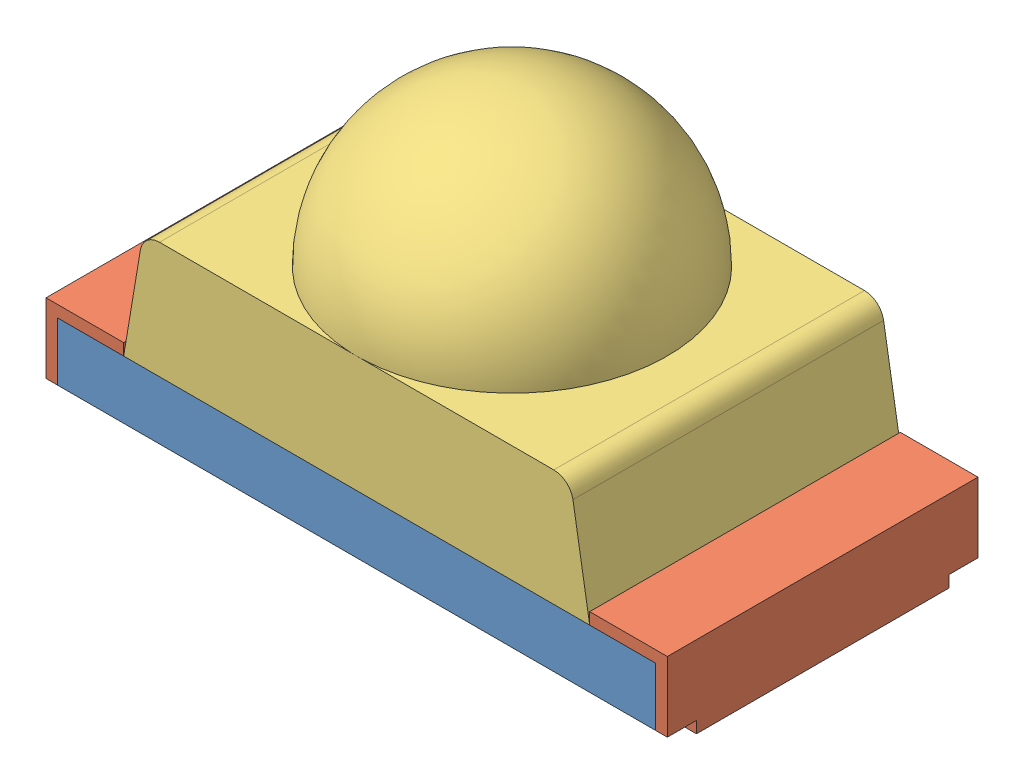
SolidWorks assembly LED0603G, configuration Default. Lengths in mm.
Overall size (1.6 0.88 0.8).
4 component instances, 3 part files, 9 mates.
Components (placement in the parent):
- LED0603-substrate-1: LED0603-substrate [Default] at (0 0.03 0) size (1.54 0.15 0.8)
- LED0603-clip-1: LED0603-clip [Default] at (-0.8 0.105 0) x (1 0 0) z (0 1 0) size (0.3 0.8 0.21)
- LED0603-clip-2: LED0603-clip [Default] at (0.8 0.105 0) x (-1 0 0) z (0 1 0) size (0.3 0.8 0.21)
- LED0603-lens-1: LED0603-lens [Default] at (0 0.18 0) size (1.2 0.7 0.8)
Mates (geometry in assembly coordinates):
- Coincident1: coincident aligned: plane of LED0603-substrate-1 through (0 0.03 0) normal (1 0 0)
- Coincident2: coincident aligned: plane of LED0603-substrate-1 through (0 0.03 0) normal (0 0 1)
- Distance1: distance = 0.03 mm aligned: plane of LED0603-substrate-1 through (0 0.03 0) normal (0 1 0)
- Coincident4: coincident anti-aligned: plane of LED0603-clip-1 through (-0.8 0.105 0) normal (0 0 -1)
- Coincident5: coincident anti-aligned: plane of LED0603-substrate-1 through (0 0.03 0) normal (0 -1 0); plane of LED0603-clip-1 through (-0.5 0.03 -0.4) normal (0 1 0)
- Coincident6: coincident anti-aligned: plane of LED0603-substrate-1 through (-0.77 0.18 0.4) normal (-1 0 0); plane of LED0603-clip-1 through (-0.77 0.18 -0.4) normal (1 0 0)
- Coincident7: coincident aligned: plane of LED0603-lens-1 through (0 0.18 0) normal (0 0 1)
- Coincident8: coincident aligned: plane of LED0603-lens-1 through (0 0.18 0) normal (1 0 0)
- Coincident9: coincident anti-aligned: plane of LED0603-substrate-1 through (0 0.18 0) normal (0 1 0); plane of LED0603-lens-1 through (0 0.18 0) normal (0 -1 0)
